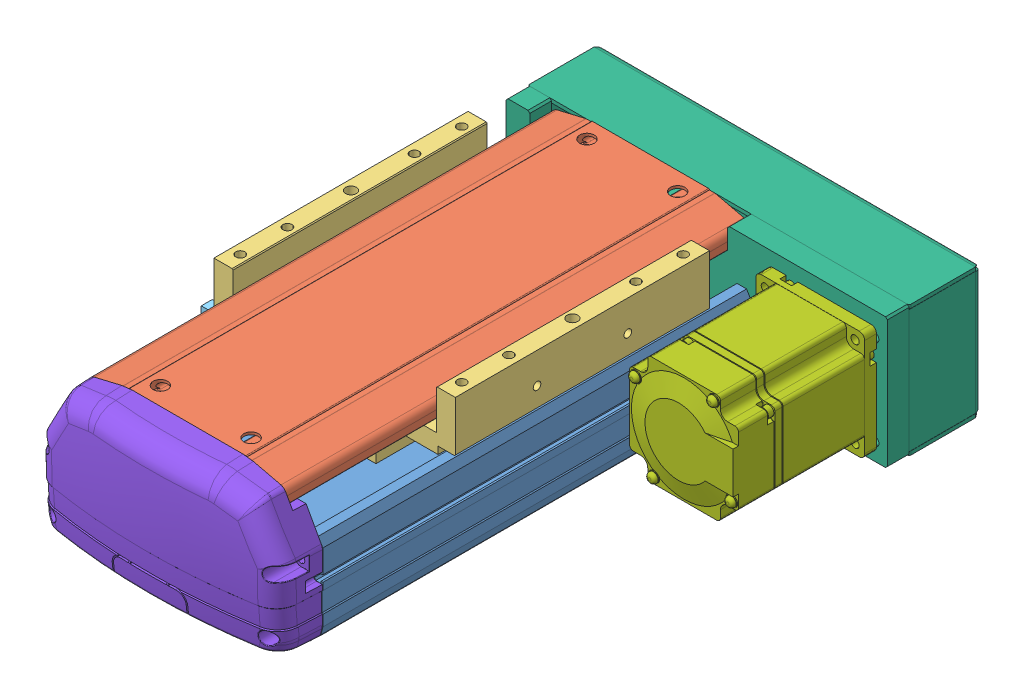
SolidWorks assembly S14-BR-200W, configuration 默认. Lengths in mm.
Overall size (223.28 78.03 318).
12 component instances, 10 part files, 33 mates.
Components (placement in the parent):
- S14-BM底座^S14-BR-200W-1: S14-BM底座^S14-BR-200W [默认] at origin size (135 48.03 259) (virtual)
- S14-BM上盖^S14-BR-200W-1: S14-BM上盖^S14-BR-200W [默认] at (0 61 -12) size (109 12.5 255) (virtual)
- S14-BR-SFSR16滑座^S14-BR-200W-1: S14-BR-SFSR16滑座^S14-BR-200W [默认] at (-1.39 35.7784 72) size (133 62 140) (virtual)
- 复件 外置感应片ST14-17^S14-BR-200W-1: 复件 外置感应片ST14-17^S14-BR-200W [默认] at (-67.4964 55 92) x (0 0 1) z (-1 0 0) size (70 30.4 7.7) (virtual)
- 复件 光电开关EE-SX672^S14-BR-200W-1: 复件 光电开关EE-SX672^S14-BR-200W [默认] at (-67.5 19.7 76) x (0 0 1) z (-1 0 0) size (26 25 13) (virtual)
- 复件 光电开关EE-SX672^S14-BR-200W-2: 复件 光电开关EE-SX672^S14-BR-200W [默认] at (-67.5 19.7 102) x (0 0 1) z (-1 0 0) size (26 25 13) (virtual)
- 复件 光电开关EE-SX672^S14-BR-200W-3: 复件 光电开关EE-SX672^S14-BR-200W [默认] at (-67.5 19.7 149) x (0 0 1) z (-1 0 0) size (26 25 13) (virtual)
- 复件 S13-14-BR电机板罩壳^S14-BR-200W-1: 复件 S13-14-BR电机板罩壳^S14-BR-200W [默认] at (34.6396 24.1 343.3649) x (1 0 0) z (0 1 0) size (210.56 52 72) (virtual)
- 复件 复件 (2) MSMD022P1AA_200W^S14-BR-200W-1: 复件 复件 (2) MSMD022P1AA_200W^S14-BR-200W [默认] at (106.5 35.4 0) x (0 0 -1) z (0 -1 0) size (109 60 60) (virtual)
- 复件 YK260EC86E1-KZ01^S14-BR-200W-1: 复件 YK260EC86E1-KZ01^S14-BR-200W [默认] at (106.5 35.4 11) x (0 -1 0) z (0 0 -1) size (60.18 72.76 137.14) (hidden, virtual)
- 复件 松下400W电机MHMF042L1U22^S14-BR-200W-1: 复件 松下400W电机MHMF042L1U22^S14-BR-200W [默认] at (320.8897 -0.4925 66.8049) x (0 0 -1) z (1 0 0) size (118 149.2 60) (hidden, virtual)
- 复件 (2) 13-14塑胶端盖^S14-BR-200W-1: 复件 (2) 13-14塑胶端盖^S14-BR-200W [Default] at (0 1 256) x (-1 0 0) z (0 0 -1) size (134.5 73.26 30.08) (virtual)
Mates (geometry in assembly coordinates):
- 距离10: distance = 73.5 mm: plane of S14-BM上盖^S14-BR-200W-1 through (-32 73.5 243) normal (0 1 0); plane of S14-BM底座^S14-BR-200W-1 through (-65.3077 0 259) normal (0 -1 0)
- 距离13: distance = 1.39 mm: plane of S14-BR-SFSR16滑座^S14-BR-200W-1 through (-1.39 35.7784 72) normal (1 0 0); plane of S14-BM底座^S14-BR-200W-1 through (0 0 0) normal (1 0 0)
- 重合155: coincident: plane of S14-BM底座^S14-BR-200W-1 through (0 0 0) normal (1 0 0); plane of S14-BM上盖^S14-BR-200W-1 through (0 61 -12) normal (1 0 0)
- 距离12: distance = 78 mm: plane of S14-BR-SFSR16滑座^S14-BR-200W-1 through (66.5036 78 22) normal (0 1 0); plane of S14-BM底座^S14-BR-200W-1 through (-65.3077 0 259) normal (0 -1 0)
- 重合166: coincident: plane of S14-BM底座^S14-BR-200W-1 through (0 0 0) normal (0 0 1); plane of assembly through (0 0 0) normal (0 0 1)
- 重合167: coincident: plane of S14-BM底座^S14-BR-200W-1 through (0 0 0) normal (0 1 0); plane of assembly through (0 0 0) normal (0 1 0)
- 重合168: coincident: plane of S14-BM底座^S14-BR-200W-1 through (0 0 0) normal (1 0 0); plane of assembly through (0 0 0) normal (1 0 0)
- 重合185: coincident: plane of S14-BR-SFSR16滑座^S14-BR-200W-1 through (-66.4964 16 9.7131) normal (-1 0 0); plane of 复件 外置感应片ST14-17^S14-BR-200W-1 through (-66.4964 55 92) normal (1 0 0)
- 同心79: concentric: cylinder of S14-BR-SFSR16滑座^S14-BR-200W-1 through (-66.9964 61 67) axis (-1 0 0) radius 2.1; cylinder of 复件 外置感应片ST14-17^S14-BR-200W-1 through (-67.4964 61 67) axis (-1 0 0) radius 2.55
- 同心80: concentric: cylinder of S14-BR-SFSR16滑座^S14-BR-200W-1 through (-66.9964 61 117) axis (-1 0 0) radius 2.1; cylinder of 复件 外置感应片ST14-17^S14-BR-200W-1 through (-67.4964 61 117) axis (-1 0 0) radius 2.55
- 重合186: coincident: plane of S14-BM底座^S14-BR-200W-1 through (-67.5 43.67 259) normal (-1 0 0); plane of 复件 光电开关EE-SX672^S14-BR-200W-1 through (-67.5 44.7 76) normal (1 0 0)
- 距离20: distance = 19.7 mm: plane of 复件 光电开关EE-SX672^S14-BR-200W-1 through (-80.5 19.7 76) normal (0 -1 0); plane of S14-BM底座^S14-BR-200W-1 through (-65.3077 0 259) normal (0 -1 0)
- 距离21: distance = 76 mm: plane of 复件 光电开关EE-SX672^S14-BR-200W-1 through (-80.5 19.7 76) normal (0 0 -1); plane of S14-BM底座^S14-BR-200W-1 through (-56.75 26.5 0) normal (0 0 -1)
- 重合189: coincident: plane of 复件 光电开关EE-SX672^S14-BR-200W-1 through (-80.5 44.7 76) normal (-1 0 0); plane of 复件 光电开关EE-SX672^S14-BR-200W-2 through (-80.5 44.7 102) normal (-1 0 0)
- 重合190: coincident: plane of 复件 光电开关EE-SX672^S14-BR-200W-1 through (-70 32.7 92) normal (0 0 1); plane of 复件 光电开关EE-SX672^S14-BR-200W-2 through (-70 32.7 92) normal (0 0 -1)
- 重合191: coincident: plane of 复件 光电开关EE-SX672^S14-BR-200W-1 through (-80.5 19.7 76) normal (0 -1 0); plane of 复件 光电开关EE-SX672^S14-BR-200W-2 through (-80.5 19.7 102) normal (0 -1 0)
- 宽度1: width: plane of 复件 外置感应片ST14-17^S14-BR-200W-1 through (-74.1964 37.6 84.5) normal (0 0 -1); plane of 复件 外置感应片ST14-17^S14-BR-200W-1 through (-74.1964 53 99.5) normal (0 0 1); plane of 复件 光电开关EE-SX672^S14-BR-200W-2 through (-80.5 19.7 102) normal (0 0 -1); plane of 复件 光电开关EE-SX672^S14-BR-200W-1 through (-80.5 19.7 82) normal (0 0 1)
- 同心81: concentric: cylinder of S14-BM底座^S14-BR-200W-1 through (62.5 39.5 259) axis (0 0 -1) radius 1.4777; cylinder of 复件 (2) 13-14塑胶端盖^S14-BR-200W-1 through (62.5 39.5 236) axis (0 0 -1) radius 2.1
- 同心82: concentric: circle of S14-BM底座^S14-BR-200W-1; cylinder of 复件 (2) 13-14塑胶端盖^S14-BR-200W-1 through (-62.5 39.5 236) axis (0 0 -1) radius 2.1
- 重合193: coincident: plane of S14-BM底座^S14-BR-200W-1 through (-100.8342 -10 236) normal (0 0 1); plane of 复件 (2) 13-14塑胶端盖^S14-BR-200W-1 through (0 1 236) normal (0 0 -1)
- 重合194: coincident: plane of 复件 光电开关EE-SX672^S14-BR-200W-2 through (-80.5 44.7 102) normal (-1 0 0); plane of 复件 光电开关EE-SX672^S14-BR-200W-3 through (-80.5 44.7 149) normal (-1 0 0)
- 重合195: coincident: plane of 复件 光电开关EE-SX672^S14-BR-200W-2 through (-80.5 19.7 102) normal (0 -1 0); plane of 复件 光电开关EE-SX672^S14-BR-200W-3 through (-80.5 19.7 149) normal (0 -1 0)
- 距离22: distance = 81 mm: plane of 复件 光电开关EE-SX672^S14-BR-200W-3 through (-80.5 19.7 155) normal (0 0 1); plane of S14-BM底座^S14-BR-200W-1 through (-100.8342 -10 236) normal (0 0 1)
- 重合197: coincident: plane of S14-BM底座^S14-BR-200W-1 through (-67.5 43.67 259) normal (-1 0 0); plane of 复件 S13-14-BR电机板罩壳^S14-BR-200W-1 through (-67.5 1 0) normal (-1 0 0)
- 重合198: coincident: plane of S14-BM底座^S14-BR-200W-1 through (-56.75 26.5 0) normal (0 0 -1); plane of 复件 S13-14-BR电机板罩壳^S14-BR-200W-1 through (37.5 37 0) normal (0 0 1)
- 距离23: distance = 1 mm: plane of 复件 S13-14-BR电机板罩壳^S14-BR-200W-1 through (-67.5 1 0) normal (0 -1 0); plane of S14-BM底座^S14-BR-200W-1 through (-65.3077 0 259) normal (0 -1 0)
- 重合200: coincident: plane of 复件 YK260EC86E1-KZ01^S14-BR-200W-1 through (79.5 8.4 0) normal (0 0 -1); plane of 复件 S13-14-BR电机板罩壳^S14-BR-200W-1 through (37.5 37 0) normal (0 0 1)
- 宽度2: width: plane of 复件 S13-14-BR电机板罩壳^S14-BR-200W-1 through (103.5 60.4 -12) normal (0 -1 0); plane of 复件 S13-14-BR电机板罩壳^S14-BR-200W-1 through (103.5 10.4 -12) normal (0 1 0); cylinder of 复件 YK260EC86E1-KZ01^S14-BR-200W-1 through (106.5 35.4 -30) axis (0 0 1) radius 4
- 距离24: distance = 30 mm: moEndPointRef_w of 复件 S13-14-BR电机板罩壳^S14-BR-200W-1; plane of 复件 YK260EC86E1-KZ01^S14-BR-200W-1 through (136.5 62.4 0) normal (1 0 0)
- 重合202: coincident: plane of S14-BM上盖^S14-BR-200W-1 through (50.5 65.3364 -12) normal (0 0 -1); line of 复件 S13-14-BR电机板罩壳^S14-BR-200W-1 through (-29 66.95 -12) axis (1 0 0)
- 宽度3: width: plane of 复件 S13-14-BR电机板罩壳^S14-BR-200W-1 through (103.5 60.4 -12) normal (0 -1 0); plane of 复件 S13-14-BR电机板罩壳^S14-BR-200W-1 through (103.5 10.4 -12) normal (0 1 0); cylinder of 复件 复件 (2) MSMD022P1AA_200W^S14-BR-200W-1 through (106.5 35.4 -14.75) axis (0 0 -1) radius 5.5
- 距离25: distance = 30 mm: plane of 复件 复件 (2) MSMD022P1AA_200W^S14-BR-200W-1 through (136.5 8.4 6.5) normal (1 0 0); unknown of 复件 S13-14-BR电机板罩壳^S14-BR-200W-1
- 重合203: coincident: plane of 复件 S13-14-BR电机板罩壳^S14-BR-200W-1 through (37.5 37 0) normal (0 0 1); plane of 复件 复件 (2) MSMD022P1AA_200W^S14-BR-200W-1 through (106.5 35.4 0) normal (0 0 -1)
